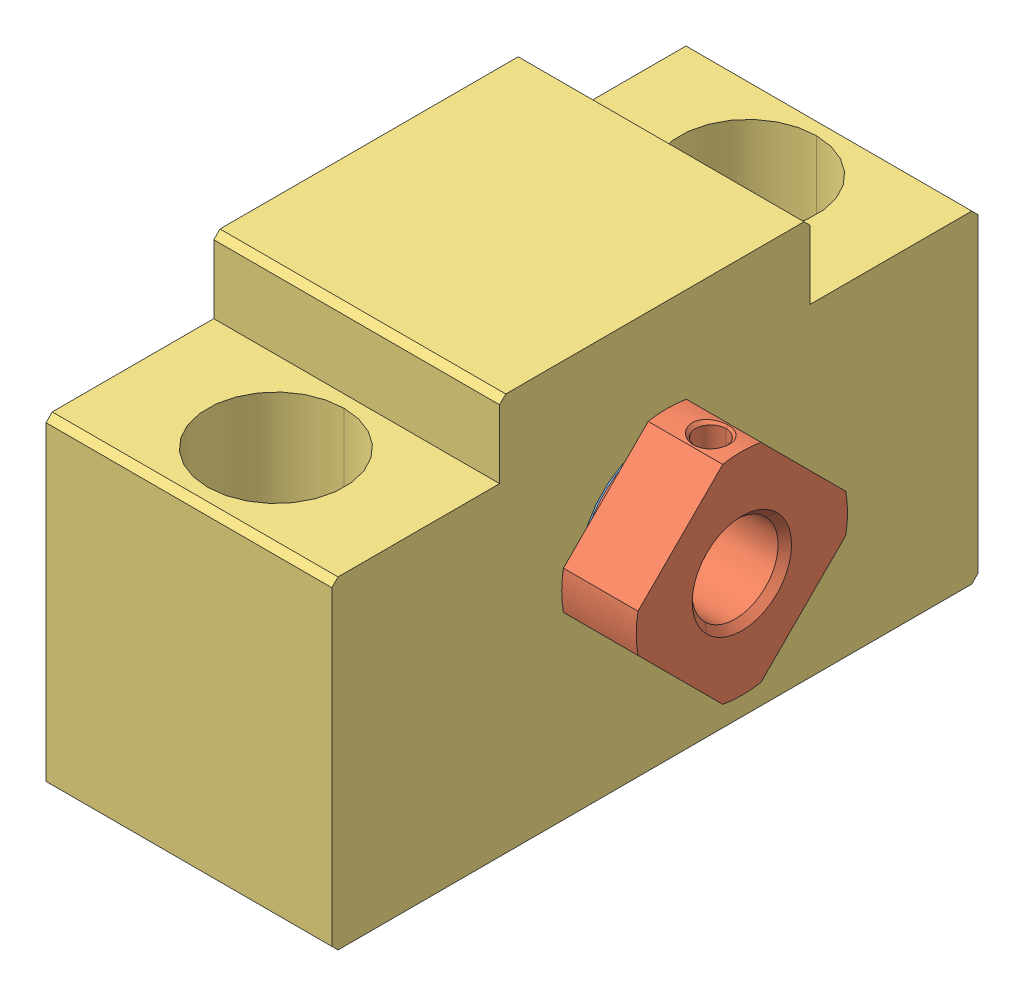
SolidWorks assembly BSW8, configuration Default. Lengths in mm.
Overall size (31.5 32 52).
4 component instances, 3 part files, 0 mates.
Components (placement in the parent):
- BSW8_3-1: BSW8_3 [Default] at (-7.5 17 0) x (0 0 -1) z (1 0 0) size (11.5 11.5 5.5)
- BSW8_5-1: BSW8_5 [Default] at (12.5 17 0) x (1 0 0) z (0 -0.707107 0.707107) size (6.5 14.07 14.07)
- BSW8_3-2: BSW8_3 [Default] at (6.5 17 0) x (0 0 -1) z (-1 0 0) size (11.5 11.5 5.5)
- BSW8_8-1: BSW8_8 [Default] at origin size (23 32 52)
